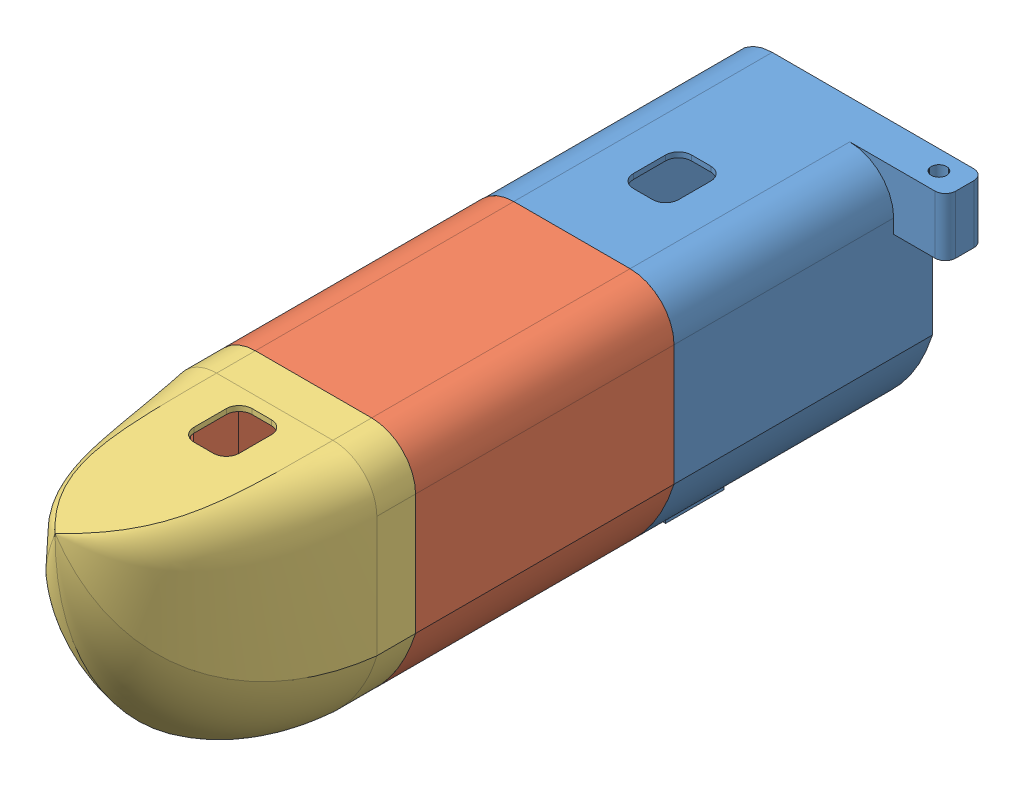
SolidWorks assembly Assemblage2, configuration Défaut. Lengths in mm.
Overall size (203.03 223.75 607.68).
3 component instances, 3 part files, 6 mates.
Components (placement in the parent):
- body_back2-1: body_back2 [Défaut] at (-8.8859 35.8046 52.2389) size (198 212 220)
- body_mid-1: body_mid [Défaut] at (-8.8859 35.8046 252.2389) size (158 208.49 220)
- body_front-1: body_front [Défaut] at (-8.8859 35.8046 452.2389) size (168.2 223.75 207.68)
Mates (geometry in assembly coordinates):
- Coïncidente1: coincident: plane of body_back2-1 through (-211.5354 24.6306 237.2389) normal (-1 0 0); plane of body_mid-1 through (-211.5354 24.6306 452.2389) normal (1 0 0)
- Coaxiale1: concentric: cylinder of body_back2-1 through (-295.1467 254.851 237.2389) axis (0 0 1) radius 346.015; cylinder of body_mid-1 through (-295.1467 254.851 452.2389) axis (0 0 -1) radius 346.015
- Coïncidente2: coincident anti-aligned: plane of body_back2-1 through (-91.5354 117.3306 252.2389) normal (0 0 1); plane of body_mid-1 through (-91.5354 117.3306 252.2389) normal (0 0 -1)
- Coaxiale2: concentric: cylinder of body_mid-1 through (22.0759 254.851 437.2389) axis (0 0 1) radius 346.015; cylinder of body_front-1 through (22.0759 254.851 482.2389) axis (0 0 -1) radius 346.015
- Coïncidente3: coincident: plane of body_mid-1 through (-61.5354 117.3306 437.2389) normal (1 0 0); plane of body_front-1 through (-61.5354 24.6306 482.2389) normal (-1 0 0)
- Coïncidente4: coincident anti-aligned: plane of body_mid-1 through (-91.5354 117.3306 452.2389) normal (0 0 1); plane of body_front-1 through (-91.5354 117.3306 452.2389) normal (0 0 -1)
